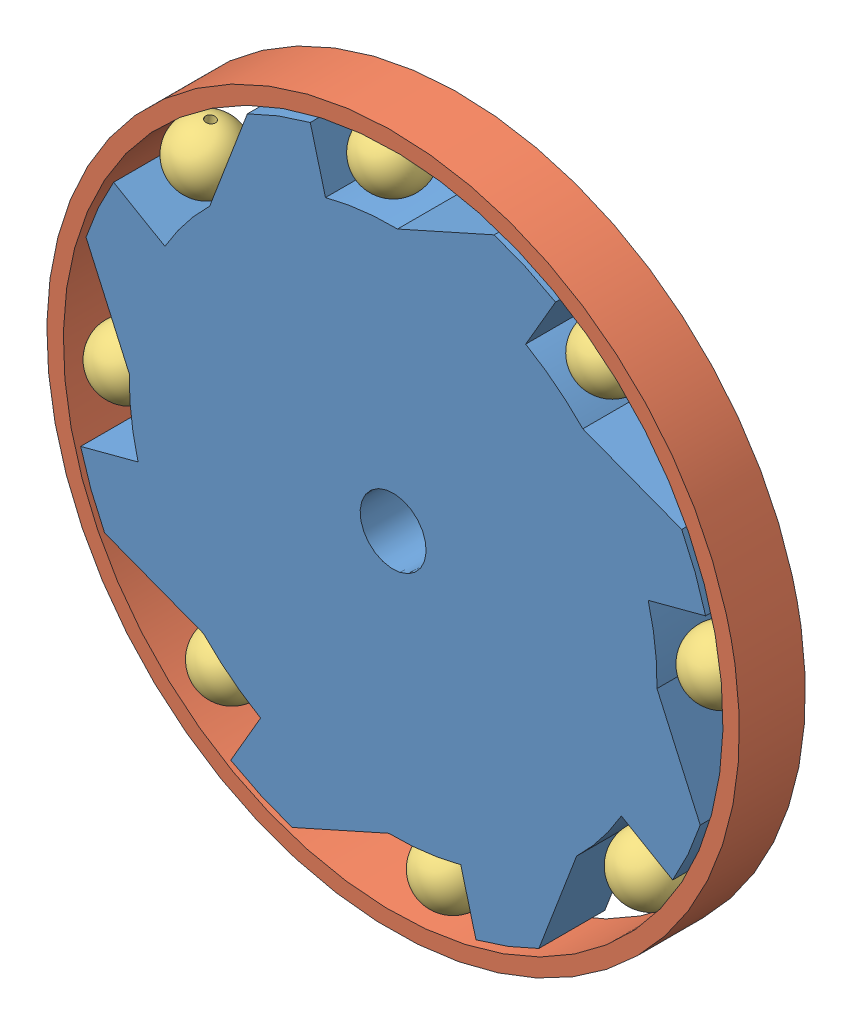
SolidWorks assembly Assem3, configuration Default. Lengths in mm.
Overall size (250.67 250.67 183.35).
10 component instances, 3 part files, 22 mates.
Components (placement in the parent):
- sw-main-part-1: sw-main-part [Default] at (22.525 136.7666 77.8498) x (0.949946 -0.312413 0) z (0 0 1) size (196 196 67.66)
- sw-ring-part-1: sw-ring-part [Default] at (22.525 136.7666 77.8498) x (0.976031 0.217634 0) z (0 0 1) size (210 210 135.69)
- sw-ball-part-1: sw-ball-part [Default] at (-67.3411 131.8599 87.8498) x (-0.803795 -0.594906 0) z (0 0 1) size (20 20 20)
- sw-ball-part-2: sw-ball-part [Default] at (-36.2827 68.6369 87.8498) x (-0.821881 -0.569659 0) z (0 0 -1) size (20 20 20)
- sw-ball-part-3: sw-ball-part [Default] at (30.6692 47.1358 87.8498) x (0.988707 0.149864 0) z (0 0 1) size (20 20 20)
- sw-ball-part-4: sw-ball-part [Default] at (90.6635 77.969 87.8498) x (0.504241 0.863563 0) z (0 0 1) size (20 20 20)
- sw-ball-part-5: sw-ball-part [Default] at (112.3854 141.7784 87.8498) x (-0.073808 -0.997272 0) z (0 0 1) size (20 20 20)
- sw-ball-part-6: sw-ball-part [Default] at (-44.0248 197.3564 87.8498) x (0.119367 0.99285 0) z (0 0 1) size (20 20 20)
- sw-ball-part-7: sw-ball-part [Default] at (12.5624 226.2135 87.8498) x (-0.337318 0.941391 0) z (0 0 1) size (20 20 20)
- sw-ball-part-8: sw-ball-part [Default] at (78.9805 206.8578 87.8498) size (20 20 20)
Mates (geometry in assembly coordinates):
- Concentric1: concentric aligned: cylinder of sw-main-part-1 through (22.525 136.7666 145.5122) axis (0 0 -1) radius 10; cylinder of sw-ring-part-1 through (22.525 136.7666 97.8498) axis (0 0 -1) radius 100
- Concentric2: concentric anti-aligned: circle of sw-main-part-1; circle of sw-ring-part-1
- Coincident2: coincident: point of sw-main-part-1; point of sw-ring-part-1
- Tangent12: tangent: cylinder of sw-ring-part-1 through (22.525 136.7666 97.8498) axis (0 0 -1) radius 100; circle of sw-ball-part-1
- Perpendicular1: perpendicular: line of sw-main-part-1 through (22.525 136.7666 77.8498) axis (0 0 1); line of sw-ball-part-1 through (-67.3411 131.8599 87.8498) axis (-0.803795 -0.594906 0)
- Tangent13: tangent anti-aligned: cylinder of sw-main-part-1 through (22.525 136.7666 97.8498) axis (0 0 -1) radius 80; sphere of sw-ball-part-1
- Tangent14: tangent: cylinder of sw-ring-part-1 through (22.525 136.7666 97.8498) axis (0 0 -1) radius 100; circle of sw-ball-part-2
- Tangent15: tangent: cylinder of sw-main-part-1 through (22.525 136.7666 97.8498) axis (0 0 -1) radius 80; circle of sw-ball-part-2
- Coincident6: coincident aligned: circle of sw-ball-part-1
- Coincident7: coincident anti-aligned: circle of sw-ball-part-2
- Coincident8: coincident aligned: circle of sw-ball-part-8
- Tangent16: tangent: cylinder of sw-main-part-1 through (22.525 136.7666 97.8498) axis (0 0 -1) radius 80; circle of sw-ball-part-8
- Coincident9: coincident aligned: circle of sw-ball-part-7
- Tangent17: tangent: cylinder of sw-main-part-1 through (22.525 136.7666 97.8498) axis (0 0 -1) radius 80; circle of sw-ball-part-7
- Coincident10: coincident aligned: circle of sw-ball-part-6
- Tangent19: tangent: cylinder of sw-main-part-1 through (22.525 136.7666 97.8498) axis (0 0 -1) radius 80; circle of sw-ball-part-6
- Coincident11: coincident aligned: circle of sw-ball-part-5
- Tangent20: tangent: cylinder of sw-main-part-1 through (22.525 136.7666 97.8498) axis (0 0 -1) radius 80; circle of sw-ball-part-5
- Coincident12: coincident aligned: circle of sw-ball-part-4
- Tangent21: tangent: cylinder of sw-main-part-1 through (22.525 136.7666 97.8498) axis (0 0 -1) radius 80; circle of sw-ball-part-4
- Coincident13: coincident aligned: circle of sw-ball-part-3
- Tangent22: tangent: cylinder of sw-main-part-1 through (22.525 136.7666 97.8498) axis (0 0 -1) radius 80; circle of sw-ball-part-3
